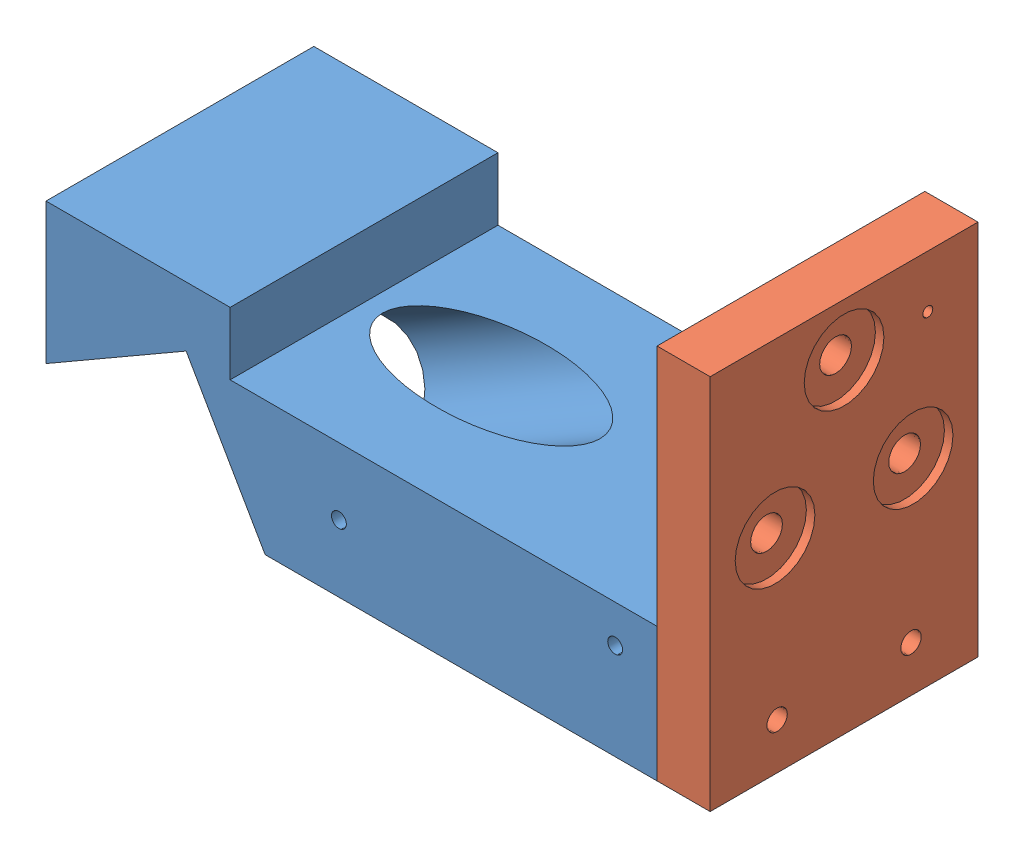
SolidWorks assembly OpticalBench_V4_Assembly, configuration Default. Lengths in mm.
Overall size (79.35 45 32).
2 component instances, 2 part files, 3 mates.
Components (placement in the parent):
- OpBench_BasePlate_Diodeblock-1: OpBench_BasePlate_Diodeblock [Manufacturing] at (20.0285 30.8072 56.8126) size (73 23.5 32)
- OpBench_BasePlate_Mirrorblock-1: OpBench_BasePlate_Mirrorblock [Manufacturing] at (62.8785 30.8072 72.8126) x (-1 0 0) z (0 0 -1) size (6.35 45 32)
Mates (geometry in assembly coordinates):
- Coincident1: coincident aligned: line of OpBench_BasePlate_Diodeblock-1 through (9.7091 30.8072 72.8126) axis (1 0 0); line of OpBench_BasePlate_Mirrorblock-1 through (56.5285 30.8072 72.8126) axis (1 0 0)
- Coincident2: coincident aligned: plane of OpBench_BasePlate_Diodeblock-1 through (-16.4715 46.8072 72.8126) normal (0 0 1); plane of OpBench_BasePlate_Mirrorblock-1 through (56.5285 75.8072 72.8126) normal (0 0 1)
- Coincident3: coincident anti-aligned: plane of OpBench_BasePlate_Diodeblock-1 through (56.5285 46.8072 40.8126) normal (1 0 0); plane of OpBench_BasePlate_Mirrorblock-1 through (56.5285 75.8072 72.8126) normal (-1 0 0)
